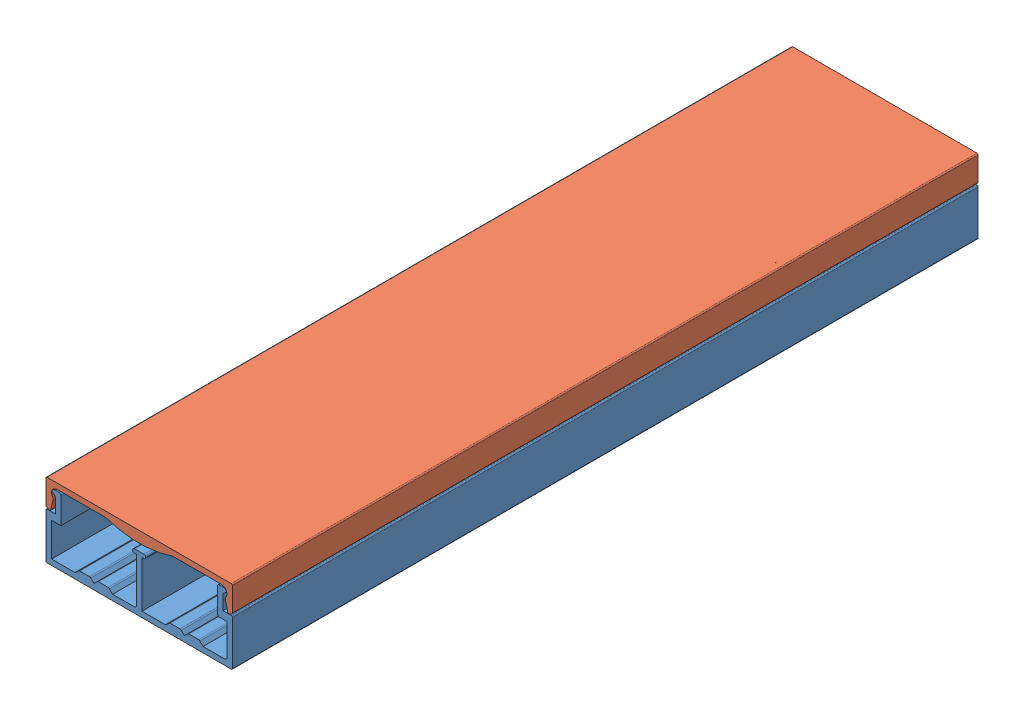
SolidWorks assembly FF2 50x20, configuration По умолчанию. Lengths in mm.
Overall size (50 19.9 200).
2 component instances, 2 part files, 2 mates.
Components (placement in the parent):
- Канал FF2 50x20-1: Канал FF2 50x20 [По умолчанию] at (142.4842 111.4187 -16.4919) size (50 18 200)
- Крышка канала FF2 50x20-1: Крышка канала FF2 50x20 [По умолчанию] at (142.4842 131.3187 -16.4919) x (-1 0 0) z (0 0 1) size (50 7.35 200)
Mates (geometry in assembly coordinates):
- Расстояние1: distance = 7.4 mm aligned: plane of Канал FF2 50x20-1 through (117.4842 123.9187 183.5081) normal (0 1 0); plane of Крышка канала FF2 50x20-1 through (142.4842 131.3187 183.5081) normal (0 1 0)
- Совпадение3: coincident aligned: plane of Канал FF2 50x20-1 through (141.2242 125.9087 183.5081) normal (0 0 1); plane of Крышка канала FF2 50x20-1 through (142.4842 155.9282 183.5081) normal (0 0 1)
